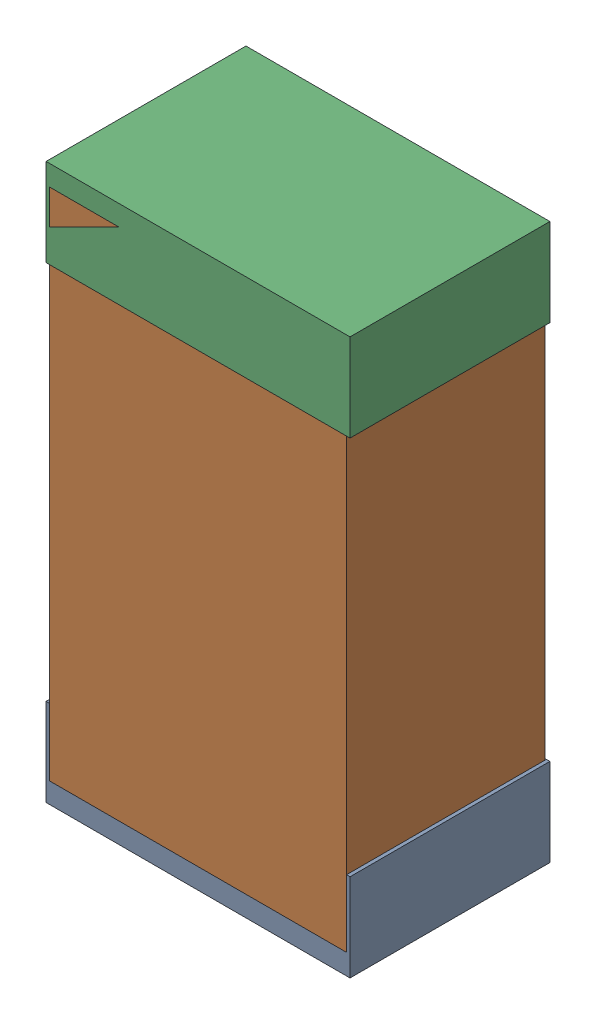
SolidWorks assembly R52Kanaloa_v2.0.0_Motor, configuration Default. Lengths in mm.
Overall size (1.3 2.38 0.85).
6 component instances, 2 part files, 0 mates.
Components (placement in the parent):
- 330415056-1: 330415056 [Default] at (95.504 147.395 -1.9574) size (1.3 0.38 0.85)
  - Extruded_2-1: Extruded_2 [Default] at origin size (1.3 0.38 0.85)
- 334787376-1: 334787376 [Default] at (95.504 148.395 -1.9524) size (1.27 2.2 0.85)
  - Extruded_16-1: Extruded_16 [Default] at origin size (1.27 2.2 0.85)
- 330415056-2: 330415056 [Default] at (95.504 149.395 -1.9574) size (1.3 0.38 0.85)
  - Extruded_2-1: Extruded_2 [Default] at origin size (1.3 0.38 0.85)
